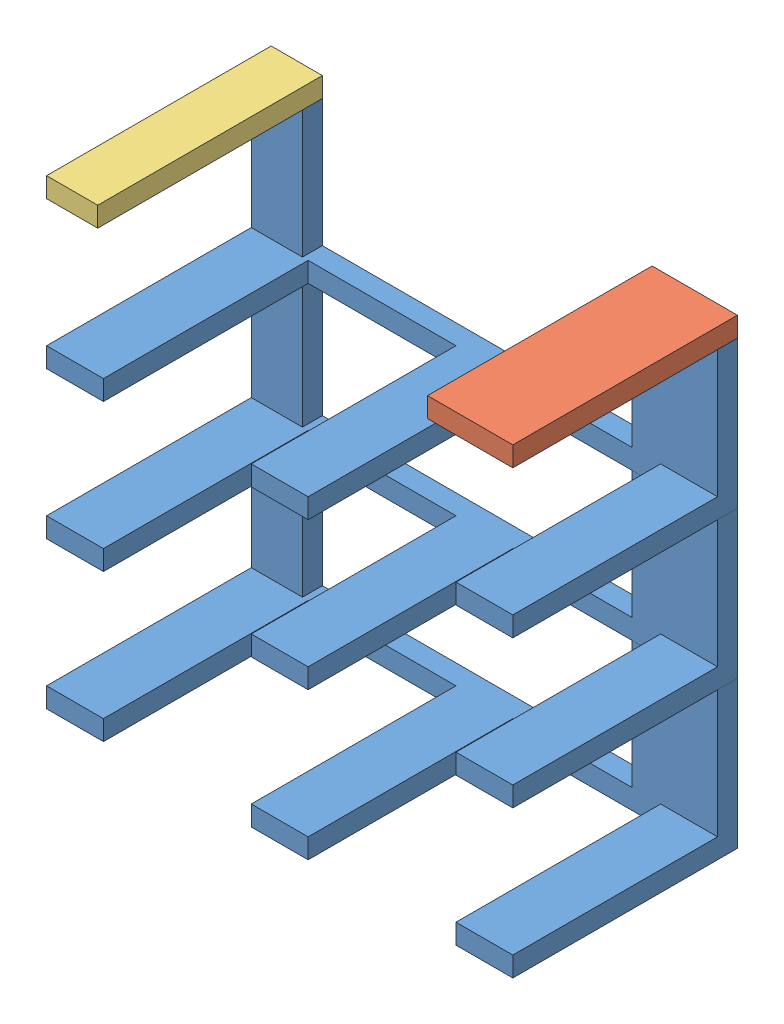
SolidWorks assembly Base Electrovalvulas, configuration Predeterminado. Lengths in mm.
Overall size (82 81.2 39.5).
5 component instances, 3 part files, 12 mates.
Components (placement in the parent):
- tope base electrovalvulas-1: tope base electrovalvulas [Predeterminado] at (-1.627 20.3518 82.0001) size (82 25.9 39.5)
- tope base electrovalvulas-2: tope base electrovalvulas [Predeterminado] at (-1.627 -5.5482 82.0001) size (82 25.9 39.5)
- tope base electrovalvulas-3: tope base electrovalvulas [Predeterminado] at (-1.627 46.2518 82.0001) size (82 25.9 39.5)
- Tope derecho base electro-1: Tope derecho base electro [Predeterminado] at (37.69 22.1467 82.0001) size (15 3.5 39.5)
- tope izquierdo base electro-2: tope izquierdo base electro [Predeterminado] at (11.1554 38.1822 82.0001) size (9 3.5 39.5)
Mates (geometry in assembly coordinates):
- Coincidente2: coincident anti-aligned: plane of tope base electrovalvulas-1 through (-60.3995 -8.1001 85.5) normal (0 -1 0); plane of tope base electrovalvulas-2 through (-1.627 -8.1001 82.0001) normal (0 1 0)
- Coincidente3: coincident aligned: plane of tope base electrovalvulas-1 through (21.6005 -8.1001 85.5) normal (1 0 0); plane of tope base electrovalvulas-2 through (21.6005 -34.0001 85.5) normal (1 0 0)
- Coincidente4: coincident aligned: plane of tope base electrovalvulas-1 through (-1.627 20.3518 82.0001) normal (0 0 -1); plane of tope base electrovalvulas-2 through (-1.627 -5.5482 82.0001) normal (0 0 -1)
- Coincidente5: coincident anti-aligned: plane of tope base electrovalvulas-1 through (-1.627 17.7999 82.0001) normal (0 1 0); plane of tope base electrovalvulas-3 through (-60.3995 17.7999 85.5) normal (0 -1 0)
- Coincidente6: coincident aligned: plane of tope base electrovalvulas-1 through (21.6005 -8.1001 85.5) normal (1 0 0); plane of tope base electrovalvulas-3 through (21.6005 17.7999 85.5) normal (1 0 0)
- Coincidente7: coincident aligned: plane of tope base electrovalvulas-1 through (-1.627 20.3518 82.0001) normal (0 0 -1); plane of tope base electrovalvulas-3 through (-1.627 46.2518 82.0001) normal (0 0 -1)
- Coincidente11: coincident: plane of tope base electrovalvulas-3 through (-1.627 43.6999 82.0001) normal (0 1 0); plane of tope izquierdo base electro-2 through (-51.3995 43.6999 121.5001) normal (0 -1 0)
- Coincidente12: coincident: plane of tope base electrovalvulas-3 through (-51.3995 43.6999 82.0001) normal (1 0 0); plane of tope izquierdo base electro-2 through (-51.3995 47.1999 121.5001) normal (1 0 0)
- Coincidente13: coincident aligned: plane of tope base electrovalvulas-3 through (-1.627 46.2518 82.0001) normal (0 0 -1); plane of tope izquierdo base electro-2 through (11.1554 38.1822 82.0001) normal (0 0 -1)
- Coincidente14: coincident: plane of tope base electrovalvulas-3 through (-1.627 46.2518 82.0001) normal (0 0 -1); plane of Tope derecho base electro-1 through (37.69 22.1467 82.0001) normal (0 0 -1)
- Coincidente15: coincident: plane of tope base electrovalvulas-3 through (21.6005 17.7999 85.5) normal (1 0 0); plane of Tope derecho base electro-1 through (21.6005 47.1999 121.5001) normal (1 0 0)
- Coincidente16: coincident anti-aligned: plane of tope base electrovalvulas-3 through (-1.627 43.6999 82.0001) normal (0 1 0); plane of Tope derecho base electro-1 through (21.6005 43.6999 121.5001) normal (0 -1 0)
